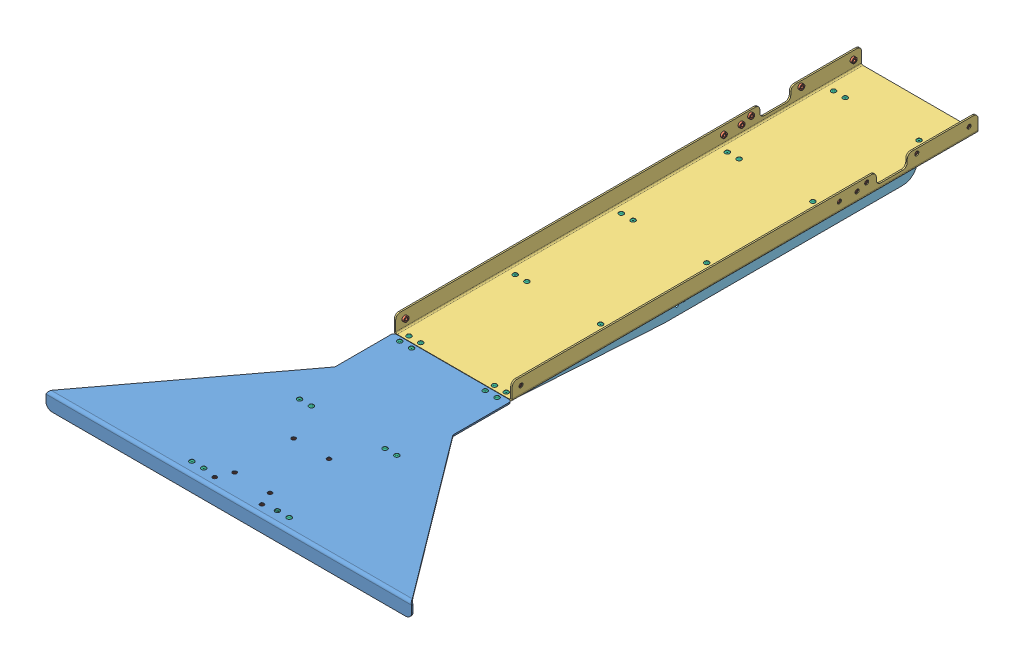
SolidWorks assembly GE-22405, configuration Default. Lengths in mm.
Overall size (788.28 338.94 1486.69).
57 component instances, 6 part files, 20 mates.
Components (placement in the parent):
- GE-22394-2: GE-22394 [Default] at (0 -3.175 1131.0938) size (788.28 306.86 482.6)
  - GE-22394-01-1: GE-22394-01 [Default] at origin size (788.28 33.34 482.6)
  - pem_clinchnut_.25_20_.054-2: pem_clinchnut_.25_20_.054 [Default] at (-50.8 4.5466 334.9625) x (0 -1 0) z (-0.471516 0 0.881858) size (5.69 11.18 11.18)
  - pem_clinchnut_.25_20_.054-3: pem_clinchnut_.25_20_.054 [Default] at (-38.1 4.5466 304.8) x (0 -1 0) z (-0.471516 0 0.881858) size (5.69 11.18 11.18)
  - pem_clinchnut_.25_20_.054-4: pem_clinchnut_.25_20_.054 [Default] at (-38.1 4.5466 177.8) x (0 -1 0) z (-0.471516 0 0.881858) size (5.69 11.18 11.18)
  - pem_clinchnut_.25_20_.054-5: pem_clinchnut_.25_20_.054 [Default] at (38.1 4.5466 177.8) x (0 -1 0) z (-0.471516 0 0.881858) size (5.69 11.18 11.18)
  - pem_clinchnut_.25_20_.054-6: pem_clinchnut_.25_20_.054 [Default] at (38.1 4.5466 304.8) x (0 -1 0) z (-0.471516 0 0.881858) size (5.69 11.18 11.18)
  - pem_clinchnut_.25_20_.054-8: pem_clinchnut_.25_20_.054 [Default] at (50.8 4.5466 334.9625) x (0 -1 0) z (0.216892 0 0.976196) size (5.69 11.18 11.18)
- GE-22395-2: GE-22395 [Default] at (0 3.175 0) size (254 38.1 1003.3)
  - GE-22395-01-1: GE-22395-01 [Default] at origin size (254 38.1 1003.3)
  - pem_clinchnut_.25_20_.054-2: pem_clinchnut_.25_20_.054 [Default] at (-125.1966 19.05 19.05) x (1 0 0) z (0 -0.006281 0.99998) size (5.69 11.18 11.18)
  - pem_clinchnut_.25_20_.054-3: pem_clinchnut_.25_20_.054 [Default] at (125.1966 19.05 19.05) x (-1 0 0) z (0 -0.796833 -0.6042) size (5.69 11.18 11.18)
  - pem_clinchnut_.25_20_.054-4: pem_clinchnut_.25_20_.054 [Default] at (125.1966 25.4 131.7625) x (-1 0 0) z (0 -0.796833 -0.6042) size (5.69 11.18 11.18)
  - pem_clinchnut_.25_20_.054-5: pem_clinchnut_.25_20_.054 [Default] at (125.1966 25.4 239.7125) x (-1 0 0) z (0 -0.796833 -0.6042) size (5.69 11.18 11.18)
  - pem_clinchnut_.25_20_.054-6: pem_clinchnut_.25_20_.054 [Default] at (125.1966 19.05 984.25) x (-1 0 0) z (0 -0.796833 -0.6042) size (5.69 11.18 11.18)
  - pem_clinchnut_.25_20_.054-7: pem_clinchnut_.25_20_.054 [Default] at (125.1966 19.05 298.45) x (-1 0 0) z (0 -0.796833 -0.6042) size (5.69 11.18 11.18)
  - pem_clinchnut_.25_20_.054-8: pem_clinchnut_.25_20_.054 [Default] at (125.1966 19.05 260.35) x (-1 0 0) z (0 -0.796833 -0.6042) size (5.69 11.18 11.18)
  - pem_clinchnut_.25_20_.054-9: pem_clinchnut_.25_20_.054 [Default] at (-125.1966 25.4 131.7625) x (1 0 0) z (0 -0.006281 0.99998) size (5.69 11.18 11.18)
  - pem_clinchnut_.25_20_.054-10: pem_clinchnut_.25_20_.054 [Default] at (-125.1966 25.4 239.7125) x (1 0 0) z (0 -0.006281 0.99998) size (5.69 11.18 11.18)
  - pem_clinchnut_.25_20_.054-11: pem_clinchnut_.25_20_.054 [Default] at (-125.1966 19.05 984.25) x (1 0 0) z (0 -0.006281 0.99998) size (5.69 11.18 11.18)
  - pem_clinchnut_.25_20_.054-12: pem_clinchnut_.25_20_.054 [Default] at (-125.1966 19.05 298.45) x (1 0 0) z (0 -0.006281 0.99998) size (5.69 11.18 11.18)
  - pem_clinchnut_.25_20_.054-13: pem_clinchnut_.25_20_.054 [Default] at (-125.1966 19.05 260.35) x (1 0 0) z (0 -0.006281 0.99998) size (5.69 11.18 11.18)
- GE-22397-1: GE-22397 [Default] at (-63.5 0 69.85) x (0 0 1) z (-1 0 0) size (1400.97 76.2 53.98)
- GE-22396-2: GE-22396 [MirrorDefault] at (63.5 0 69.85) x (0 0 1) z (-1 0 0) size (1400.97 76.2 53.98)
- rivet_.1875_.126-.25-52: rivet_.1875_.126-.25 [Default] at (-104.775 3.175 993.775) x (0.957018 0 -0.29003) z (0 1 0) size (10.01 10.01 13.03)
- rivet_.1875_.126-.25-1: rivet_.1875_.126-.25 [Default] at (-79.375 3.175 1461.2938) x (-0.837169 0 -0.546944) z (0 1 0) size (10.01 10.01 13.03)
- rivet_.1875_.126-.25-24: rivet_.1875_.126-.25 [Default] at (79.375 3.175 1461.2938) x (-0.837169 0 0.546944) z (0 1 0) size (10.01 10.01 13.03)
- rivet_.1875_.126-.25-53: rivet_.1875_.126-.25 [Default] at (-104.775 3.175 1229.5187) x (-0.837169 0 -0.546944) z (0 1 0) size (10.01 10.01 13.03)
- rivet_.1875_.126-.25-54: rivet_.1875_.126-.25 [Default] at (-79.375 3.175 1229.5187) x (-0.837169 0 -0.546944) z (0 1 0) size (10.01 10.01 13.03)
- rivet_.1875_.126-.25-55: rivet_.1875_.126-.25 [Default] at (79.375 3.175 1229.5187) x (-0.837169 0 -0.546944) z (0 1 0) size (10.01 10.01 13.03)
- rivet_.1875_.126-.25-56: rivet_.1875_.126-.25 [Default] at (104.775 3.175 1229.5187) x (-0.837169 0 -0.546944) z (0 1 0) size (10.01 10.01 13.03)
- rivet_.1875_.126-.25-57: rivet_.1875_.126-.25 [Default] at (-104.775 3.175 1461.2938) x (-0.837169 0 -0.546944) z (0 1 0) size (10.01 10.01 13.03)
- rivet_.1875_.126-.25-58: rivet_.1875_.126-.25 [Default] at (-104.775 3.175 1013.6187) x (-0.837169 0 -0.546944) z (0 1 0) size (10.01 10.01 13.03)
- rivet_.1875_.126-.25-59: rivet_.1875_.126-.25 [Default] at (104.775 3.175 1013.6187) x (-0.837169 0 -0.546944) z (0 1 0) size (10.01 10.01 13.03)
- rivet_.1875_.126-.25-60: rivet_.1875_.126-.25 [Default] at (79.375 3.175 1013.6187) x (-0.837169 0 -0.546944) z (0 1 0) size (10.01 10.01 13.03)
- rivet_.1875_.126-.25-61: rivet_.1875_.126-.25 [Default] at (104.775 3.175 1461.2938) x (-0.837169 0 -0.546944) z (0 1 0) size (10.01 10.01 13.03)
- rivet_.1875_.126-.25-62: rivet_.1875_.126-.25 [Default] at (79.375 3.175 1461.2938) x (-0.837169 0 -0.546944) z (0 1 0) size (10.01 10.01 13.03)
- rivet_.1875_.126-.25-63: rivet_.1875_.126-.25 [Default] at (-79.375 3.175 1013.6187) x (-0.837169 0 -0.546944) z (0 1 0) size (10.01 10.01 13.03)
- rivet_.1875_.126-.25-64: rivet_.1875_.126-.25 [Default] at (104.775 3.175 79.375) x (0.957018 0 -0.29003) z (0 1 0) size (10.01 10.01 13.03)
- rivet_.1875_.126-.25-65: rivet_.1875_.126-.25 [Default] at (-79.375 3.175 993.775) x (0.957018 0 -0.29003) z (0 1 0) size (10.01 10.01 13.03)
- rivet_.1875_.126-.25-66: rivet_.1875_.126-.25 [Default] at (79.375 3.175 993.775) x (0.957018 0 -0.29003) z (0 1 0) size (10.01 10.01 13.03)
- rivet_.1875_.126-.25-67: rivet_.1875_.126-.25 [Default] at (104.775 3.175 993.775) x (0.957018 0 -0.29003) z (0 1 0) size (10.01 10.01 13.03)
- rivet_.1875_.126-.25-68: rivet_.1875_.126-.25 [Default] at (104.775 3.175 765.175) x (0.957018 0 -0.29003) z (0 1 0) size (10.01 10.01 13.03)
- rivet_.1875_.126-.25-69: rivet_.1875_.126-.25 [Default] at (79.375 3.175 765.175) x (0.957018 0 -0.29003) z (0 1 0) size (10.01 10.01 13.03)
- rivet_.1875_.126-.25-70: rivet_.1875_.126-.25 [Default] at (-104.775 3.175 765.175) x (0.957018 0 -0.29003) z (0 1 0) size (10.01 10.01 13.03)
- rivet_.1875_.126-.25-71: rivet_.1875_.126-.25 [Default] at (-104.775 3.175 536.575) x (0.957018 0 -0.29003) z (0 1 0) size (10.01 10.01 13.03)
- rivet_.1875_.126-.25-72: rivet_.1875_.126-.25 [Default] at (-79.375 3.175 536.575) x (0.957018 0 -0.29003) z (0 1 0) size (10.01 10.01 13.03)
- rivet_.1875_.126-.25-73: rivet_.1875_.126-.25 [Default] at (-79.375 3.175 765.175) x (0.957018 0 -0.29003) z (0 1 0) size (10.01 10.01 13.03)
- rivet_.1875_.126-.25-74: rivet_.1875_.126-.25 [Default] at (79.375 3.175 536.575) x (0.957018 0 -0.29003) z (0 1 0) size (10.01 10.01 13.03)
- rivet_.1875_.126-.25-75: rivet_.1875_.126-.25 [Default] at (104.775 3.175 536.575) x (0.957018 0 -0.29003) z (0 1 0) size (10.01 10.01 13.03)
- rivet_.1875_.126-.25-76: rivet_.1875_.126-.25 [Default] at (104.775 3.175 307.975) x (0.957018 0 -0.29003) z (0 1 0) size (10.01 10.01 13.03)
- rivet_.1875_.126-.25-77: rivet_.1875_.126-.25 [Default] at (79.375 3.175 307.975) x (0.957018 0 -0.29003) z (0 1 0) size (10.01 10.01 13.03)
- rivet_.1875_.126-.25-78: rivet_.1875_.126-.25 [Default] at (-79.375 3.175 307.975) x (0.957018 0 -0.29003) z (0 1 0) size (10.01 10.01 13.03)
- rivet_.1875_.126-.25-79: rivet_.1875_.126-.25 [Default] at (-104.775 3.175 307.975) x (0.957018 0 -0.29003) z (0 1 0) size (10.01 10.01 13.03)
- rivet_.1875_.126-.25-80: rivet_.1875_.126-.25 [Default] at (-104.775 3.175 79.375) x (0.957018 0 -0.29003) z (0 1 0) size (10.01 10.01 13.03)
- rivet_.1875_.126-.25-81: rivet_.1875_.126-.25 [Default] at (-79.375 3.175 79.375) x (0.957018 0 -0.29003) z (0 1 0) size (10.01 10.01 13.03)
- rivet_.1875_.126-.25-82: rivet_.1875_.126-.25 [Default] at (79.375 3.175 79.375) x (0.957018 0 -0.29003) z (0 1 0) size (10.01 10.01 13.03)
Mates (geometry in assembly coordinates):
- Coincident1: coincident aligned: plane of GE-22395-2 through (0 3.175 0) normal (1 0 0)
- Coincident2: coincident aligned: plane of GE-22395-2 through (0 3.175 0) normal (0 0 1)
- Coincident3: coincident anti-aligned: plane of GE-22395-2/GE-22395-01-1 through (0 0 0) normal (0 -1 0)
- Coincident8: coincident aligned: plane of GE-22395-2/GE-22395-01-1 through (0 3.175 0) normal (0 1 0); plane of GE-22394-2/GE-22394-01-1 through (0 3.175 1131.0938) normal (0 1 0)
- Width1: width anti-aligned: plane of GE-22395-2/GE-22395-01-1 through (-127 3.175 0) normal (-1 0 0); plane of GE-22394-2/GE-22394-01-1 through (127 3.175 0) normal (1 0 0); plane of GE-22395-2/GE-22395-01-1 through (127 3.175 1131.0938) normal (1 0 0); plane of GE-22394-2/GE-22394-01-1 through (-127 3.175 1131.0938) normal (-1 0 0)
- Distance1: distance = 0.7937 mm anti-aligned: plane of GE-22395-2/GE-22395-01-1 through (-127 0 1003.3) normal (0 0 1); plane of GE-22394-2/GE-22394-01-1 through (-127 3.175 1004.0938) normal (0 0 -1)
- Coincident10: coincident anti-aligned: plane of GE-22395-2/GE-22395-01-1 through (0 0 0) normal (0 -1 0); plane of GE-22397-1 through (-63.5 0 69.85) normal (0 1 0)
- Coincident13: coincident anti-aligned: plane of GE-22395-2/GE-22395-01-1 through (0 0 0) normal (0 -1 0); plane of back angle to chute-1 through (-63.5 0 -153.1937) normal (0 1 0)
- Concentric10: concentric aligned: circle of sheet metal_trap-1; circle of rivet_.1875_.126-.25-1
- Coincident20: coincident aligned: plane of GE-22394-2/GE-22394-01-1 through (0 3.175 1131.0938) normal (0 1 0); circle of rivet_.1875_.126-.25-1
- Coincident5863: coincident anti-aligned: plane of GE-22394-2/GE-22394-01-1 through (0 -3.175 1486.6937) normal (0 0 1); plane of GE-22401-1 through (393.7 -1.5875 1486.6937) normal (0 0 -1)
- Coincident5864: coincident aligned: plane of GE-22394-2/GE-22394-01-1 through (-393.7 0 1486.6937) normal (-1 0 0); plane of GE-22401-1 through (-393.7 -31.75 1485.1063) normal (-1 0 0)
- Coincident5865: coincident anti-aligned: plane of GE-22394-2/GE-22394-01-1 through (-393.7 -30.1625 1486.6937) normal (0 -1 0); plane of GE-22401-1 through (393.7 -30.1625 1486.6937) normal (0 1 0)
- Concentric6584: concentric aligned: cylinder of GE-22395-2/GE-22395-01-1 through (-104.775 3.175 536.575) axis (0 1 0) radius 2.4574; cylinder of GE-22397-1 through (-104.775 0 536.575) axis (0 1 0) radius 2.4574
- Concentric6585: concentric aligned: cylinder of GE-22395-2/GE-22395-01-1 through (-79.375 3.175 536.575) axis (0 1 0) radius 2.4574; cylinder of GE-22397-1 through (-79.375 0 536.575) axis (0 1 0) radius 2.4574
- Concentric6586: concentric aligned: circle of GE-22395-1; circle of rivet_.1875_.126-.25-52
- Coincident5866: coincident aligned: plane of GE-22395-2/GE-22395-01-1 through (0 3.175 0) normal (0 1 0); circle of rivet_.1875_.126-.25-52
- Coincident5867: coincident anti-aligned: plane of GE-22395-2/GE-22395-01-1 through (0 0 0) normal (0 -1 0); plane of GE-22396-2 through (63.5 0 69.85) normal (0 1 0)
- Concentric6588: concentric aligned: cylinder of GE-22395-2/GE-22395-01-1 through (79.375 3.175 993.775) axis (0 1 0) radius 2.4574; cylinder of GE-22396-2 through (79.375 0 993.775) axis (0 1 0) radius 2.4574
- Concentric6589: concentric aligned: cylinder of GE-22395-2/GE-22395-01-1 through (79.375 3.175 79.375) axis (0 1 0) radius 2.4574; cylinder of GE-22396-2 through (79.375 0 79.375) axis (0 1 0) radius 2.4574
